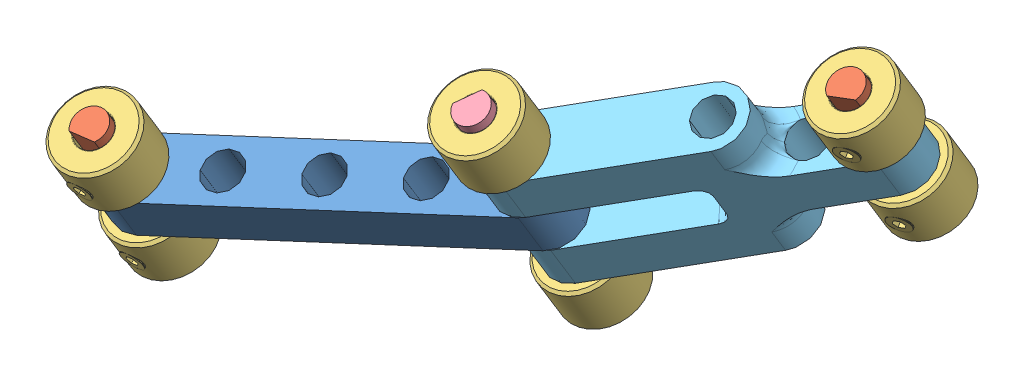
SolidWorks assembly Link Assembly, configuration Default. Lengths in mm.
Overall size (55.24 31.38 38.78).
11 component instances, 5 part files, 31 mates.
Components (placement in the parent):
- Base Link-1: Base Link [Default] at (197.5277 -2.253 -4.4836) x (0.901914 0.22428 -0.369121) z (0 0.854612 0.519267) size (35.35 5.35 4.5)
- Aluminum D Shaft-1: Aluminum D Shaft [Default] at (183.999 -5.6172 1.0532) x (0 -0.854612 -0.519267) z (-0.995127 -0.051201 0.084268) size (16 2.4 2.9)
- 6056N11_Carbon Steel Set Screw Collar-1: 6056N11_Carbon Steel Set Screw Collar [6056N11] at (183.999 -11.8131 -2.7114) x (-0.995127 -0.051201 0.084268) z (0 0.854612 0.519267) size (7 7.1 5)
- 6056N11_Carbon Steel Set Screw Collar-2: 6056N11_Carbon Steel Set Screw Collar [6056N11] at (183.999 -3.6943 2.2216) x (-0.995127 -0.051201 0.084268) z (0 0.854612 0.519267) size (7 7.1 5)
- Aluminum D Shaft-2: Aluminum D Shaft [Default] at (230.9028 9.0055 -23.0128) x (0 0.854612 0.519267) z (0.941762 0.17462 -0.28739) size (16 2.4 2.9)
- 6056N11_Carbon Steel Set Screw Collar-3: 6056N11_Carbon Steel Set Screw Collar [6056N11] at (230.9028 2.8095 -26.7775) x (-0.941762 -0.17462 0.28739) z (0 0.854612 0.519267) size (7 7.1 5)
- 6056N11_Carbon Steel Set Screw Collar-4: 6056N11_Carbon Steel Set Screw Collar [6056N11] at (230.9028 10.9284 -21.8445) x (-0.941762 -0.17462 0.28739) z (0 0.854612 0.519267) size (7 7.1 5)
- Link D Shaft-1: Link D Shaft [Default] at (211.0564 1.1112 -10.0204) x (0 -0.854612 -0.519267) z (0.552359 0.432864 -0.71241) size (25 2.4 2.9)
- 6056N11_Carbon Steel Set Screw Collar-5: 6056N11_Carbon Steel Set Screw Collar [6056N11] at (211.0564 -8.9305 -16.1218) x (0.552359 0.432864 -0.71241) z (0 0.854612 0.519267) size (7 7.1 5)
- 6056N11_Carbon Steel Set Screw Collar-6: 6056N11_Carbon Steel Set Screw Collar [6056N11] at (211.0564 6.8798 -6.5153) x (0.552359 0.432864 -0.71241) z (0 0.854612 0.519267) size (7 7.1 5)
- Upper Link-2: Upper Link [Default] at (218.995 4.2689 -15.2173) x (0.793853 0.315771 -0.519697) z (0 0.854612 0.519267) size (30.35 5.35 13.5)
Mates (geometry in assembly coordinates):
- Concentric30: concentric aligned: cylinder of Base Link-1 through (211.0564 3.0341 -8.852) axis (0 -0.854612 -0.519267) radius 1.675; cylinder of Upper Link-1 through (199.4791 31.9793 -36.1428) axis (0 -0.854612 -0.519267) radius 1.51
- Coincident32: coincident aligned: plane of Base Link-1 through (197.5277 -2.253 -4.4836) normal (0 0.854612 0.519267); plane of Upper Link-1 through (206.0825 22.3111 -33.2299) normal (0 0.854612 0.519267)
- Concentric52: concentric aligned: cylinder of Aluminum D Shaft-1 through (183.999 1.2197 5.2074) axis (0 -0.854612 -0.519267) radius 1.45; cylinder of 6056N11_Carbon Steel Set Screw Collar-1 through (183.999 -7.5401 -0.1151) axis (0 -0.854612 -0.519267) radius 1.5
- Parallel22: parallel aligned: plane of Aluminum D Shaft-1 through (184.0927 0.7288 6.0153) normal (0.098603 -0.516737 0.850447); plane of 6056N11_Carbon Steel Set Screw Collar-1 through (184.3441 -11.4852 1.5633) normal (0.098603 -0.516737 0.850447)
- Concentric53: concentric aligned: cylinder of Aluminum D Shaft-1 through (183.999 1.2197 5.2074) axis (0 -0.854612 -0.519267) radius 1.45; cylinder of 6056N11_Carbon Steel Set Screw Collar-2 through (183.999 0.5787 4.8179) axis (0 -0.854612 -0.519267) radius 1.5
- Parallel23: parallel aligned: plane of Aluminum D Shaft-1 through (184.0927 0.7288 6.0153) normal (0.098603 -0.516737 0.850447); plane of 6056N11_Carbon Steel Set Screw Collar-2 through (184.3441 -3.3664 6.4963) normal (0.098603 -0.516737 0.850447)
- Coincident134: coincident aligned: plane of Base Link-1 through (197.5277 -2.253 -4.4836) normal (0 0.854612 0.519267); plane of Aluminum D Shaft-2 through (230.9028 9.0055 -23.0128) normal (0 0.854612 0.519267)
- Concentric78: concentric anti-aligned: cylinder of Aluminum D Shaft-2 through (230.9028 2.1686 -27.1669) axis (0 0.854612 0.519267) radius 1.45; cylinder of 6056N11_Carbon Steel Set Screw Collar-4 through (230.9028 15.2014 -19.2481) axis (0 -0.854612 -0.519267) radius 1.5
- Concentric79: concentric anti-aligned: cylinder of Aluminum D Shaft-2 through (230.9028 2.1686 -27.1669) axis (0 0.854612 0.519267) radius 1.45; cylinder of 6056N11_Carbon Steel Set Screw Collar-3 through (230.9028 7.0826 -24.1812) axis (0 -0.854612 -0.519267) radius 1.5
- Parallel31: parallel aligned: plane of Aluminum D Shaft-2 through (231.2222 1.704 -26.4023) normal (0.336281 -0.489026 0.804841); plane of 6056N11_Carbon Steel Set Screw Collar-3 through (232.0797 3.2345 -22.6624) normal (0.336281 -0.489026 0.804841)
- Parallel32: parallel aligned: plane of Aluminum D Shaft-2 through (231.2222 1.704 -26.4023) normal (0.336281 -0.489026 0.804841); plane of 6056N11_Carbon Steel Set Screw Collar-4 through (232.0797 11.3533 -17.7293) normal (0.336281 -0.489026 0.804841)
- Coincident178: coincident anti-aligned: plane of Upper Link-1 through (206.0825 22.3111 -33.2299) normal (0 0.854612 0.519267); plane of Link D Shaft-1 through (211.0564 1.1112 -10.0204) normal (0 -0.854612 -0.519267)
- Concentric113: concentric anti-aligned: cylinder of Upper Link-1 through (199.4791 20.4421 -43.1529) axis (0 0.854612 0.519267) radius 1.51; cylinder of Link D Shaft-1 through (211.0564 11.7938 -3.5295) axis (0 -0.854612 -0.519267) radius 1.45
- Concentric114: concentric aligned: cylinder of Link D Shaft-1 through (211.0564 11.7938 -3.5295) axis (0 -0.854612 -0.519267) radius 1.45; cylinder of 6056N11_Carbon Steel Set Screw Collar-5 through (211.0564 -4.6574 -13.5254) axis (0 -0.854612 -0.519267) radius 1.5
- Parallel33: parallel aligned: plane of Link D Shaft-1 through (210.2645 12.0663 -3.978) normal (-0.833606 0.286822 -0.472053); plane of 6056N11_Carbon Steel Set Screw Collar-5 through (208.1388 -5.7901 -16.4758) normal (-0.833606 0.286822 -0.472053)
- Concentric115: concentric aligned: cylinder of Link D Shaft-1 through (211.0564 11.7938 -3.5295) axis (0 -0.854612 -0.519267) radius 1.45; cylinder of 6056N11_Carbon Steel Set Screw Collar-6 through (211.0564 11.1529 -3.919) axis (0 -0.854612 -0.519267) radius 1.5
- Parallel34: parallel aligned: plane of Link D Shaft-1 through (210.2645 12.0663 -3.978) normal (-0.833606 0.286822 -0.472053); plane of 6056N11_Carbon Steel Set Screw Collar-6 through (208.1388 10.0202 -6.8693) normal (-0.833606 0.286822 -0.472053)
- Coincident179: coincident anti-aligned: plane of Upper Link-1 through (206.0825 16.5425 -36.735) normal (0 -0.854612 -0.519267); plane of 6056N11_Carbon Steel Set Screw Collar-5 through (211.0564 -4.6574 -13.5254) normal (0 0.854612 0.519267)
- Coincident181: coincident anti-aligned: plane of Upper Link-1 through (206.0825 28.0798 -29.7249) normal (0 0.854612 0.519267); plane of 6056N11_Carbon Steel Set Screw Collar-6 through (211.0564 6.8798 -6.5153) normal (0 -0.854612 -0.519267)
- Concentric130: concentric anti-aligned: cylinder of Link D Shaft-1 through (211.0564 11.7938 -3.5295) axis (0 -0.854612 -0.519267) radius 1.45; cylinder of Upper Link-2 through (211.0564 -4.6574 -13.5254) axis (0 0.854612 0.519267) radius 1.675
- Concentric131: concentric anti-aligned: cylinder of Aluminum D Shaft-2 through (230.9028 2.1686 -27.1669) axis (0 0.854612 0.519267) radius 1.45; cylinder of Upper Link-2 through (230.9028 10.9284 -21.8445) axis (0 -0.854612 -0.519267) radius 1.675
- Concentric132: concentric anti-aligned: cylinder of Base Link-1 through (211.0564 3.0341 -8.852) axis (0 -0.854612 -0.519267) radius 1.675; cylinder of Upper Link-2 through (211.0564 -4.6574 -13.5254) axis (0 0.854612 0.519267) radius 1.675
- Coincident204: coincident anti-aligned: plane of 6056N11_Carbon Steel Set Screw Collar-5 through (211.0564 -4.6574 -13.5254) normal (0 0.854612 0.519267); plane of Upper Link-2 through (222.9642 0.0791 -21.3209) normal (0 -0.854612 -0.519267)
- Coincident205: coincident anti-aligned: plane of 6056N11_Carbon Steel Set Screw Collar-6 through (211.0564 6.8798 -6.5153) normal (0 -0.854612 -0.519267); plane of Upper Link-2 through (222.9642 11.6164 -14.3108) normal (0 0.854612 0.519267)
- Coincident206: coincident anti-aligned: plane of Link D Shaft-1 through (211.0564 1.1112 -10.0204) normal (0 -0.854612 -0.519267); plane of Upper Link-2 through (218.995 4.2689 -15.2173) normal (0 0.854612 0.519267)
- Coincident207: coincident aligned: plane of Base Link-1 through (197.5277 -2.253 -4.4836) normal (0 0.854612 0.519267); plane of Upper Link-2 through (218.995 4.2689 -15.2173) normal (0 0.854612 0.519267)
- Parallel35: parallel aligned: plane of Aluminum D Shaft-2 through (231.2222 1.704 -26.4023) normal (0.336281 -0.489026 0.804841); plane of 6056N11_Carbon Steel Set Screw Collar-4 through (232.0797 11.3533 -17.7293) normal (0.336281 -0.489026 0.804841)
- Parallel36: parallel aligned: plane of Aluminum D Shaft-2 through (231.2222 1.704 -26.4023) normal (0.336281 -0.489026 0.804841); plane of 6056N11_Carbon Steel Set Screw Collar-3 through (232.0797 3.2345 -22.6624) normal (0.336281 -0.489026 0.804841)
- Concentric133: concentric aligned: cylinder of Base Link-1 through (183.999 -3.6943 2.2216) axis (0 -0.854612 -0.519267) radius 1.675; cylinder of Aluminum D Shaft-1 through (183.999 1.2197 5.2074) axis (0 -0.854612 -0.519267) radius 1.45
- Coincident212: coincident anti-aligned: plane of Base Link-1 through (197.5277 -2.253 -4.4836) normal (0 0.854612 0.519267); plane of Aluminum D Shaft-1 through (183.999 -5.6172 1.0532) normal (0 -0.854612 -0.519267)
- Parallel37: parallel aligned: plane of Aluminum D Shaft-1 through (184.0927 0.7288 6.0153) normal (0.098603 -0.516737 0.850447); plane of 6056N11_Carbon Steel Set Screw Collar-2 through (184.3441 -3.3664 6.4963) normal (0.098603 -0.516737 0.850447)
